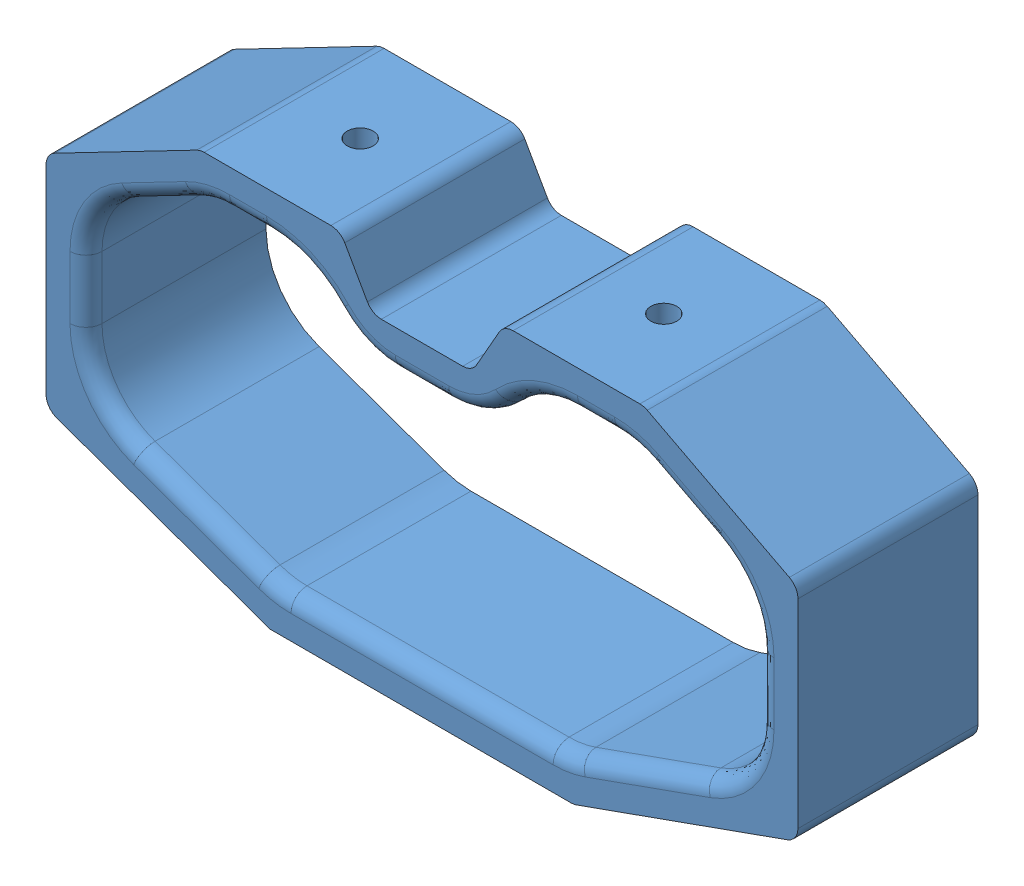
SolidWorks assembly Hand, configuration Default. Lengths in mm.
Overall size (217.7 47.5 234.33).
2 component instances, 2 part files, 3 mates.
Components (placement in the parent):
- Hand_Reference-1: Hand_Reference [Default] at (-262.0076 234.3277 62.8615) size (217.7 0 234.33)
- Hand_Mount-1: Hand_Mount [Default] at (-269.8014 258.0777 -15.8193) x (-1 0 0) z (0 0 1) size (94 47.5 22.5)
Mates (geometry in assembly coordinates):
- Coincident8: coincident: line of Hand_Reference-1 through (-262.0076 234.3277 62.8615) axis (-0.098574 0 -0.99513); point of Hand_Mount-1
- Parallel5: parallel: line of Hand_Reference-1 through (-262.0076 234.3277 62.8615) axis (0 0 1); plane of Hand_Mount-1 through (-316.8014 248.0777 6.6807) normal (-1 0 0)
- Parallel7: parallel anti-aligned: plane of Hand_Reference-1 through (-262.0076 234.3277 62.8615) normal (0 1 0); plane of Hand_Mount-1 through (-250.8264 210.5777 6.6807) normal (0 -1 0)
